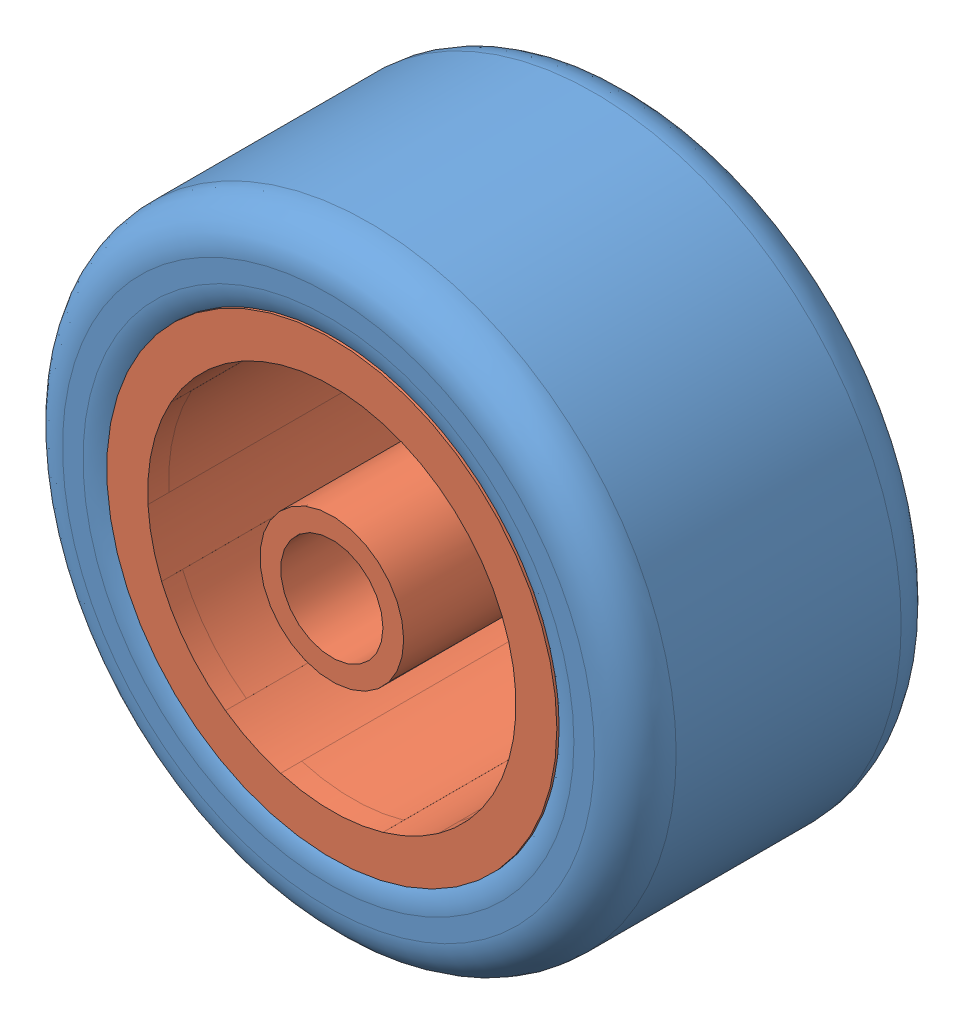
SolidWorks assembly wheel complete, configuration Default. Lengths in mm.
Overall size (30 30 15).
2 component instances, 2 part files, 1 mates.
Components (placement in the parent):
- wheel tire-1: wheel tire [Default] at origin size (30 30 15)
- wheel for robot-2: wheel for robot [Default] at (0 0 7.8348) x (0 0 -1) z (1 0 0) size (14 22 22)
Mates (geometry in assembly coordinates):
- Concentric1: concentric anti-aligned: cylinder of wheel tire-1 through (0 0 15) axis (0 0 -1) radius 13; cylinder of wheel for robot-2 through (0 0 7.8348) axis (0 0 1) radius 10
